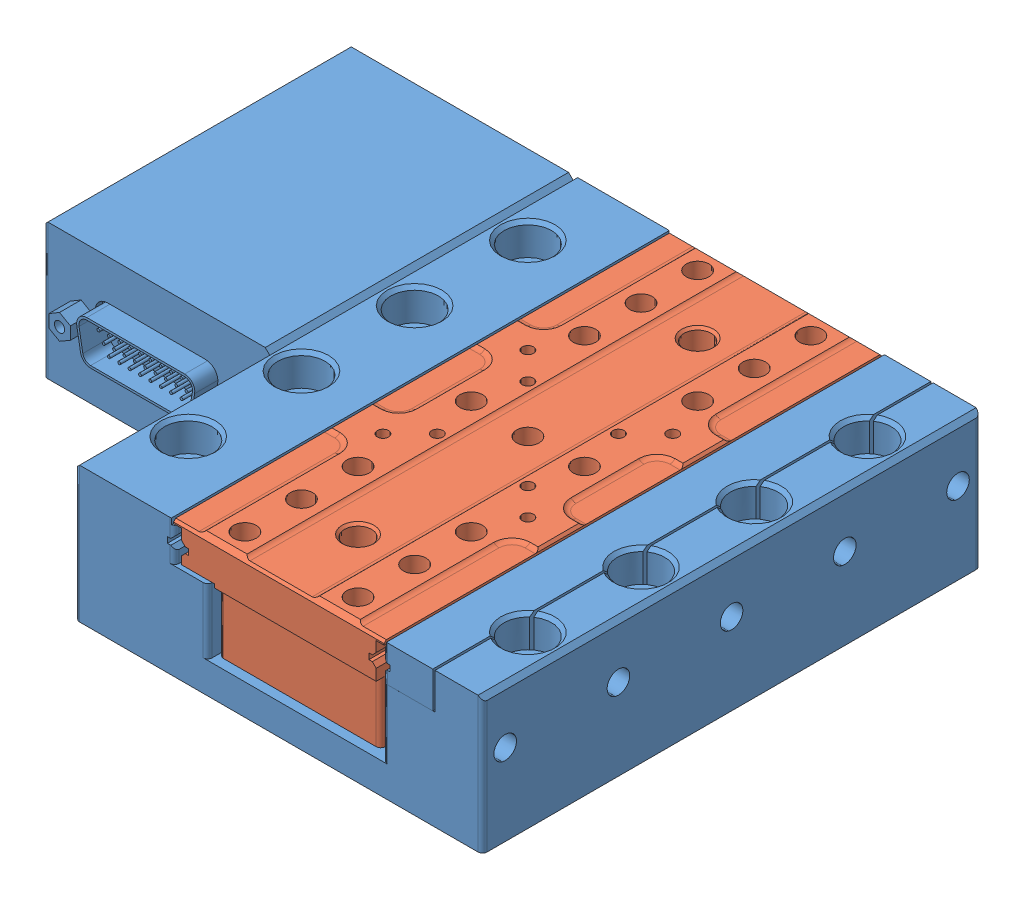
SolidWorks assembly LDA, configuration LDA025A-AE53T10A. Lengths in mm.
Overall size (140 31 110).
2 component instances, 2 part files, 6 mates.
Components (placement in the parent):
- LDA_base^LDA-1: LDA_base^LDA [LDA025-T10] at origin size (140 30.5 110) (virtual)
- LDA_carriage^LDA-1: LDA_carriage^LDA [LDA025] at origin (virtual)
Mates (geometry in assembly coordinates):
- Coincident1: coincident aligned: plane of LDA_carriage^LDA-1 through (0 0 0) normal (1 0 0); plane of assembly through (0 0 0) normal (1 0 0)
- Coincident2: coincident aligned: plane of LDA_carriage^LDA-1 through (0 0 0) normal (0 1 0); plane of LDA_base^LDA-1 through (0 0 0) normal (0 1 0)
- LimitDistance1: limit distance = 0 mm aligned: plane of LDA_carriage^LDA-1 through (0 0 0) normal (0 0 1); plane of LDA_base^LDA-1 through (0 0 0) normal (0 0 1)
- Coincident3: coincident aligned: plane of LDA_base^LDA-1; plane of assembly through (0 0 0) normal (1 0 0)
- Coincident4: coincident anti-aligned: plane of LDA_base^LDA-1 through (0 0 0) normal (0 -1 0); plane of assembly through (0 0 0) normal (0 1 0)
- Coincident5: coincident aligned: plane of LDA_base^LDA-1 through (0 0 0) normal (0 0 1); plane of assembly through (0 0 0) normal (0 0 1)
